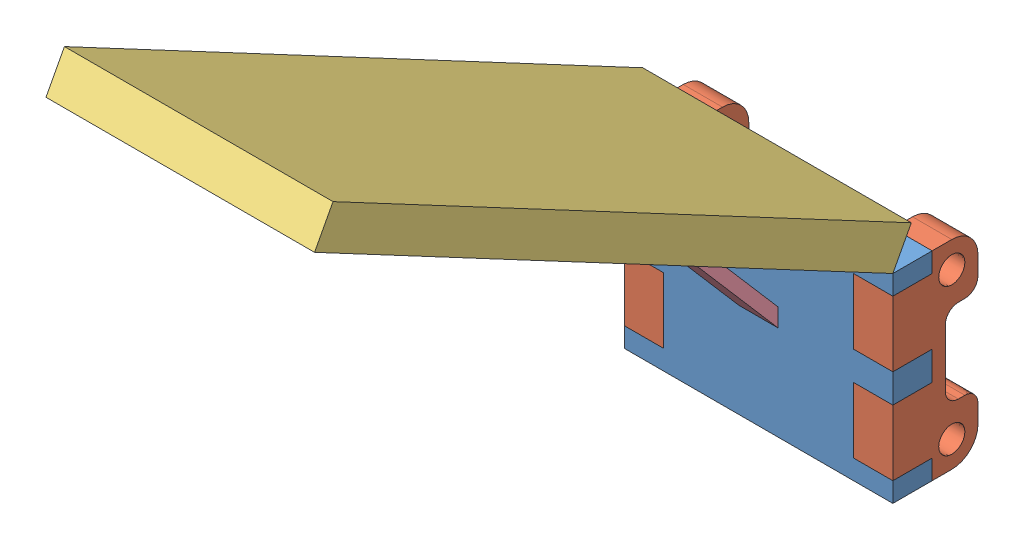
SolidWorks assembly Pièce Complète, configuration Défaut. Lengths in mm.
Overall size (41 82.64 101.29).
5 component instances, 4 part files, 12 mates.
Components (placement in the parent):
- Pièce 1-1: Pièce 1 [Défaut] at (7.3153 -0.7246 42.7154) size (41 30.4 6)
- Pièce 2-1: Pièce 2 [Défaut] at (-7.1847 -1.4132 48.7152) x (0 0 1) z (-1 0 0) size (13 30.4 6)
- Pièce 3-1: Pièce 3 [Défaut] at (9.0296 36.1196 77.937) x (0 0.469472 0.882948) z (1 0 0) size (100 6 41)
- Pièce 2-2: Pièce 2 [Défaut] at (27.8153 -1.4132 48.7152) x (0 0 1) z (-1 0 0) size (13 30.4 6)
- Pièce 4-1: Pièce 4 [Défaut] at (4.3153 11.0741 55.3322) x (0 0.757109 0.653288) z (1 0 0) size (38.95 1.81 6)
Mates (geometry in assembly coordinates):
- Coïncidente1: coincident anti-aligned: plane of Pièce 1-1 through (-7.1847 10.7868 48.7154) normal (-1 0 0); plane of Pièce 2-1 through (-7.1847 9.7868 39.7154) normal (1 0 0)
- Coïncidente2: coincident anti-aligned: plane of Pièce 1-1 through (-13.1847 10.7868 48.7154) normal (0 -1 0); plane of Pièce 2-1 through (-13.1847 10.7868 48.7154) normal (0 1 0)
- Coïncidente3: coincident anti-aligned: line of Pièce 1-1 through (-7.1847 10.7868 48.7154) axis (0 -1 0); line of Pièce 2-1 through (-7.1847 0.7868 48.7154) axis (0 1 0)
- Coïncidente8: coincident anti-aligned: plane of Pièce 1-1 through (27.8153 10.7868 48.7154) normal (0 -1 0); plane of Pièce 2-2 through (21.8153 10.7868 48.7154) normal (0 1 0)
- Coïncidente9: coincident anti-aligned: plane of Pièce 1-1 through (21.8153 10.7868 48.7154) normal (1 0 0); plane of Pièce 2-2 through (21.8153 9.7868 39.7154) normal (-1 0 0)
- Coïncidente10: coincident aligned: line of Pièce 1-1 through (21.8153 0.7868 48.7154) axis (0 1 0); line of Pièce 2-2 through (21.8153 0.7868 48.7154) axis (0 1 0)
- Coïncidente11: coincident anti-aligned: line of Pièce 1-1 through (27.8153 13.7868 48.7154) axis (-1 0 0); line of Pièce 3-1 through (-13.1847 13.7868 48.7154) axis (1 0 0)
- Coïncidente12: coincident: point of Pièce 1-1; point of Pièce 3-1
- Distance1: distance = 0 mm anti-aligned: plane of Pièce 4-1 through (10.3153 0.6011 48.7154) normal (0 0 -1); plane of Pièce 1-1 through (7.3153 -0.7246 48.7154) normal (0 0 1)
- Distance3: distance = 17.5 mm: point of Pièce 4-1; line of Pièce 1-1 through (27.8153 -3.6132 48.7154) axis (0 1 0)
- Distance4: distance = 17.5 mm: point of Pièce 4-1; line of Pièce 1-1 through (-13.1847 0.7868 48.7154) axis (0 -1 0)
- Coïncidente22: coincident anti-aligned: plane of Pièce 3-1 through (9.0296 30.8219 80.7538) normal (0 -0.882948 0.469472); plane of Pièce 4-1 through (10.3153 27.3165 74.161) normal (0 0.882948 -0.469472)
